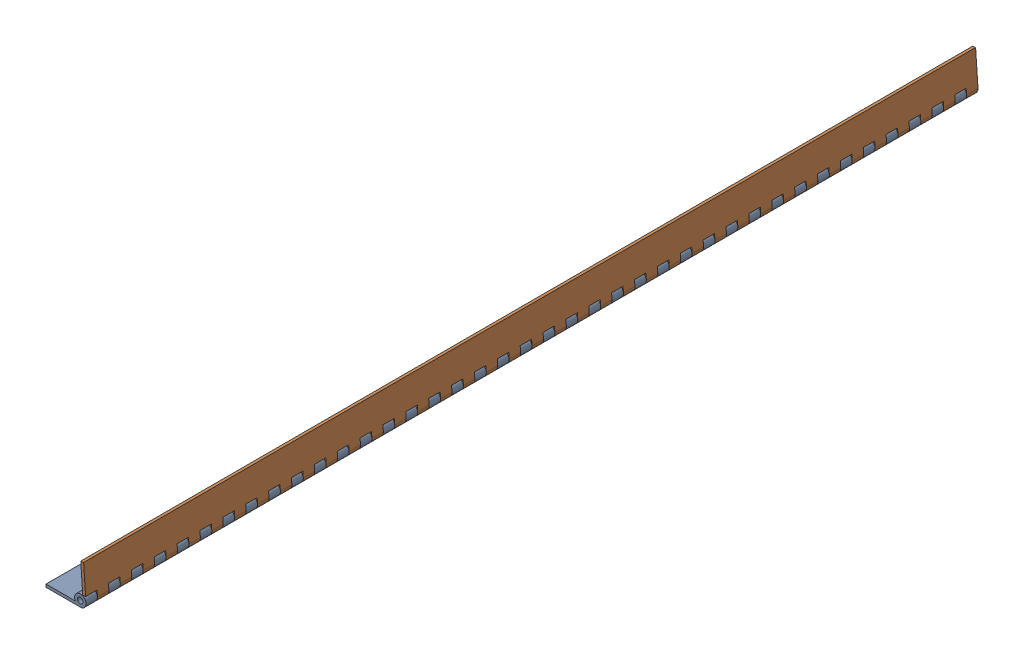
SolidWorks assembly FE-00014-02ASSY_, configuration Default. Lengths in mm.
Overall size (44.88 45.23 990.6).
2 component instances, 1 part files, 0 mates.
Components (placement in the parent):
- FE-00014-02_-1: FE-00014-02_ [Default] at origin size (44.45 12.7 990.6)
- FE-00014-02_-2: FE-00014-02_ [Default] at (3.381 3.6257 990.6) x (0.069756 -0.997564 0) z (0 0 -1) size (44.45 12.7 990.6)
